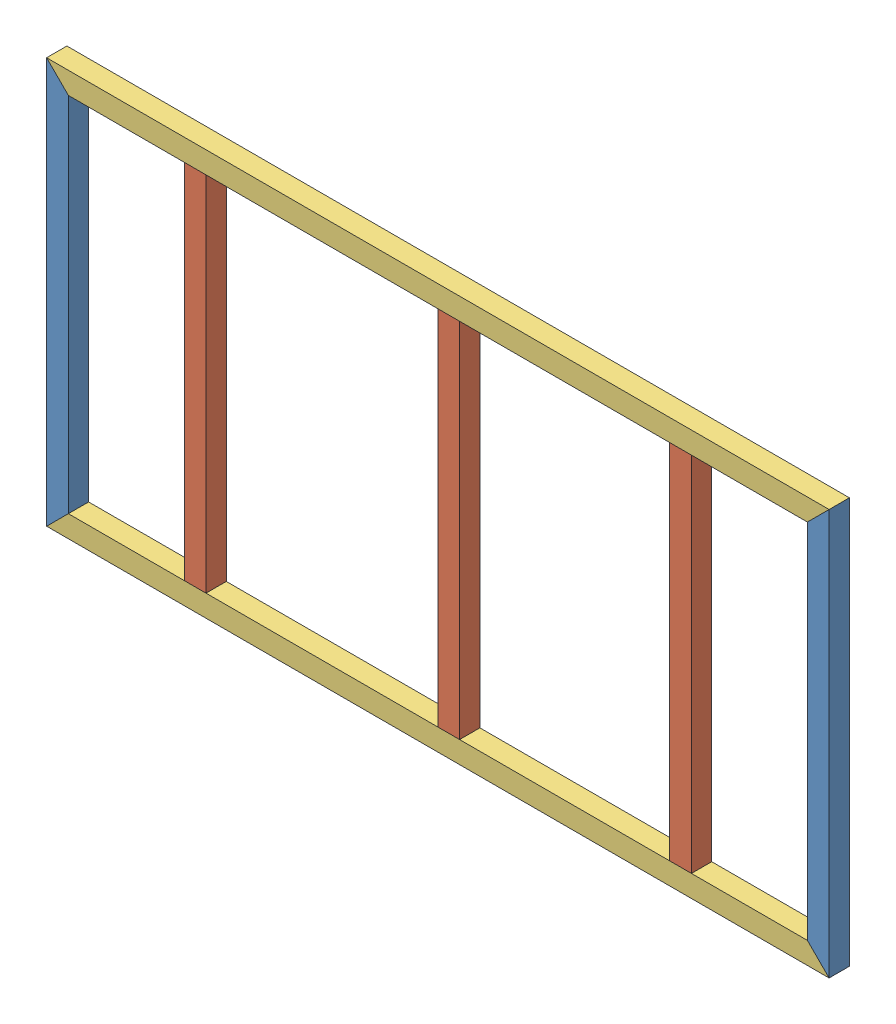
SolidWorks assembly Рама, configuration По умолчанию. Lengths in mm.
Overall size (2700 1400 70).
7 component instances, 3 part files, 21 mates.
Components (placement in the parent):
- Боковина-1: Боковина [По умолчанию] at (-1312.5 1400 -35) x (0 -1 0) z (0 0 1) size (1400 75 70)
- Перемычка-1: Перемычка [По умолчанию] at (-837.5 75 -35) x (0 1 0) z (0 0 1) size (1250 75 70)
- ПрофильН-1: ПрофильН [По умолчанию] at (-1350 37.5 -35) size (2700 75 70)
- Перемычка-2: Перемычка [По умолчанию] at (37.5 75 -35) x (0 1 0) z (0 0 1) size (1250 75 70)
- Перемычка-3: Перемычка [По умолчанию] at (837.5 75 -35) x (0 1 0) z (0 0 1) size (1250 75 70)
- Боковина-2: Боковина [По умолчанию] at (1312.5 1400 -35) x (0 -1 0) z (0 0 -1) size (1400 75 70)
- ПрофильН-2: ПрофильН [По умолчанию] at (-1350 1362.5 -35) x (1 0 0) z (0 0 -1) size (2700 75 70)
Mates (geometry in assembly coordinates):
- Совпадение1: coincident aligned: plane of ПрофильН-1 through (1350 75 0) normal (0 0 1); plane of assembly through (0 0 0) normal (0 0 1)
- Совпадение2: coincident anti-aligned: plane of ПрофильН-1 through (1350 0 0) normal (0 -1 0); plane of assembly through (0 0 0) normal (0 1 0)
- Расстояние1: distance = 1350 mm: point of assembly; point of ПрофильН-1
- Совпадение5: coincident: plane of Боковина-1 through (-1275 0 0) normal (0 0 1); plane of ПрофильН-1 through (1350 75 0) normal (0 0 1)
- Совпадение6: coincident anti-aligned: plane of Боковина-1 through (-1350 0 0) normal (0.707107 -0.707107 0); plane of ПрофильН-1 through (-1275 75 0) normal (-0.707107 0.707107 0)
- Совпадение7: coincident aligned: plane of Перемычка-1 through (-875 1325 -70) normal (0 0 -1); plane of ПрофильН-1 through (1350 75 -70) normal (0 0 -1)
- Совпадение8: coincident anti-aligned: plane of Перемычка-1 through (-837.5 75 -35) normal (0 -1 0); plane of ПрофильН-1 through (1350 75 0) normal (0 1 0)
- Расстояние2: distance = 400 mm anti-aligned: plane of Боковина-1 through (-1275 0 0) normal (1 0 0); plane of Перемычка-1 through (-875 1325 0) normal (-1 0 0)
- Совпадение10: coincident aligned: line of Боковина-1 through (-1350 0 0) axis (0 0 -1); line of ПрофильН-1 through (-1350 0 0) axis (0 0 -1)
- Совпадение11: coincident anti-aligned: plane of ПрофильН-1 through (1350 0 0) normal (0.707107 0.707107 0); plane of Боковина-2 through (1350 0 -70) normal (-0.707107 -0.707107 0)
- Совпадение12: coincident anti-aligned: line of ПрофильН-1 through (1350 0 0) axis (0 0 -1); line of Боковина-2 through (1350 0 -70) axis (0 0 1)
- Совпадение13: coincident aligned: plane of ПрофильН-1 through (1350 75 -70) normal (0 0 -1); plane of Боковина-2 through (1275 0 -70) normal (0 0 -1)
- Совпадение14: coincident aligned: plane of ПрофильН-1 through (1350 75 -70) normal (0 0 -1); plane of Перемычка-3 through (800 1325 -70) normal (0 0 -1)
- Совпадение15: coincident anti-aligned: plane of ПрофильН-1 through (1350 75 0) normal (0 1 0); plane of Перемычка-3 through (837.5 75 -35) normal (0 -1 0)
- Совпадение16: coincident aligned: plane of ПрофильН-1 through (1350 75 -70) normal (0 0 -1); plane of Перемычка-2 through (0 1325 -70) normal (0 0 -1)
- Совпадение17: coincident anti-aligned: plane of ПрофильН-1 through (1350 75 0) normal (0 1 0); plane of Перемычка-2 through (37.5 75 -35) normal (0 -1 0)
- Совпадение18: coincident anti-aligned: plane of Боковина-2 through (1275 1325 -70) normal (-0.707107 0.707107 0); plane of ПрофильН-2 through (1350 1400 -70) normal (0.707107 -0.707107 0)
- Совпадение19: coincident aligned: line of Боковина-2 through (1350 1400 -70) axis (0 0 1); line of ПрофильН-2 through (1350 1400 -70) axis (0 0 1)
- Совпадение20: coincident aligned: plane of Боковина-2 through (1275 0 -70) normal (0 0 -1); plane of ПрофильН-2 through (1350 1325 -70) normal (0 0 -1)
- Расстояние3: distance = 400 mm anti-aligned: plane of Боковина-2 through (1275 0 -70) normal (-1 0 0); plane of Перемычка-3 through (875 1325 0) normal (1 0 0)
- Расстояние5: distance = 800 mm anti-aligned: plane of Перемычка-2 through (0 1325 0) normal (-1 0 0); plane of Перемычка-1 through (-800 1325 0) normal (1 0 0)
